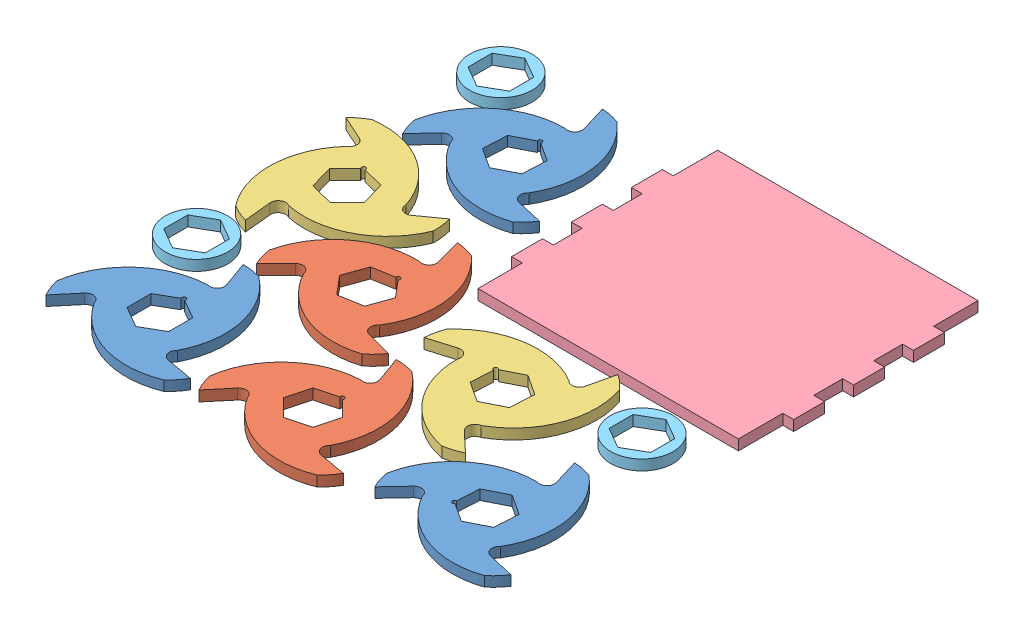
SolidWorks assembly Assem2, configuration Default. Lengths in mm.
Overall size (338.61 15.62 329.49).
11 component instances, 5 part files, 9 mates.
Components (placement in the parent):
- Cutter_1-1: Cutter_1 [Default] at origin size (280.09 6.1 281.96)
- Cutter_1-2: Cutter_1 [Default] at (202.8694 0 3.5857) x (-0.450502 0 -0.892776) z (0.892776 0 -0.450502) size (280.09 6.1 281.96)
- Cutter_2-3: Cutter_2 [Default] at (96.8019 -0.127 3.5112) size (280.09 6.35 281.96)
- Cutter_2-4: Cutter_2 [Default] at (49.566 -0.127 -77.0389) x (0.996481 0 0.083817) z (-0.083817 0 0.996481) size (280.09 6.35 281.96)
- Cutter_3-3: Cutter_3 [Default] at (144.4365 -0.127 -64.4428) x (0.058163 0 -0.998307) z (0.998307 0 0.058163) size (280.09 6.35 281.96)
- Cutter_3-4: Cutter_3 [Default] at (-10.0512 -0.127 -124.1155) x (0.700476 0 -0.713676) z (0.713676 0 0.700476) size (280.09 6.35 281.96)
- BackPlate-1: BackPlate [Default] at (163.6523 -0.127 -182.6784) x (1 0 0) z (0 1 0) size (171.96 146.05 6.35)
- Cutter_1-3: Cutter_1 [Default] at (24.7899 0 -191.6066) x (0.998672 0 0.051524) z (-0.051524 0 0.998672) size (280.09 6.1 281.96)
- Hex_Spacer-1: Hex_Spacer [Default] at (217.1138 6.223 -76.7597) x (1 0 0) z (0 -1 0) size (38.1 38.1 6.35)
- Hex_Spacer-2: Hex_Spacer [Default] at (-27.1703 3.048 -49.5604) x (1 0 0) z (0 -1 0) size (38.1 38.1 6.35)
- Hex_Spacer-3: Hex_Spacer [Default] at (-25.8998 -3.048 -233.7824) x (1 0 0) z (0 -1 0) size (38.1 38.1 6.35)
Mates (geometry in assembly coordinates):
- Coincident11: coincident: plane of Cutter_1-1 through (0 3.048 0) normal (0 1 0); plane of Cutter_3-3 through (144.4365 3.048 -64.4428) normal (0 1 0)
- Coincident12: coincident: plane of Cutter_2-3 through (96.8019 3.048 3.5112) normal (0 1 0); plane of Cutter_3-3 through (144.4365 3.048 -64.4428) normal (0 1 0)
- Coincident13: coincident: plane of Cutter_1-1 through (0 3.048 0) normal (0 1 0); plane of BackPlate-1 through (163.6523 3.048 -182.6784) normal (0 1 0)
- Parallel1: parallel: line of BackPlate-1 through (84.2773 3.048 -109.6534) axis (1 0 0); line of assembly
- Coincident15: coincident: plane of Cutter_1-1 through (0 3.048 0) normal (0 1 0); plane of Cutter_1-2 through (202.8694 3.048 3.5857) normal (0 1 0)
- Coincident16: coincident: plane of Cutter_1-1 through (0 3.048 0) normal (0 1 0); plane of Cutter_2-4 through (49.566 3.048 -77.0389) normal (0 1 0)
- Coincident17: coincident: plane of Cutter_1-1 through (0 3.048 0) normal (0 1 0); plane of Cutter_3-4 through (-10.0512 3.048 -124.1155) normal (0 1 0)
- Coincident18: coincident: plane of Cutter_1-1 through (0 3.048 0) normal (0 1 0); plane of Cutter_1-3 through (24.7899 3.048 -191.6066) normal (0 1 0)
- Coincident19: coincident: plane of Cutter_1-1 through (0 3.048 0) normal (0 1 0); plane of Hex_Spacer-1 through (217.1138 3.048 -76.7597) normal (0 -1 0)
